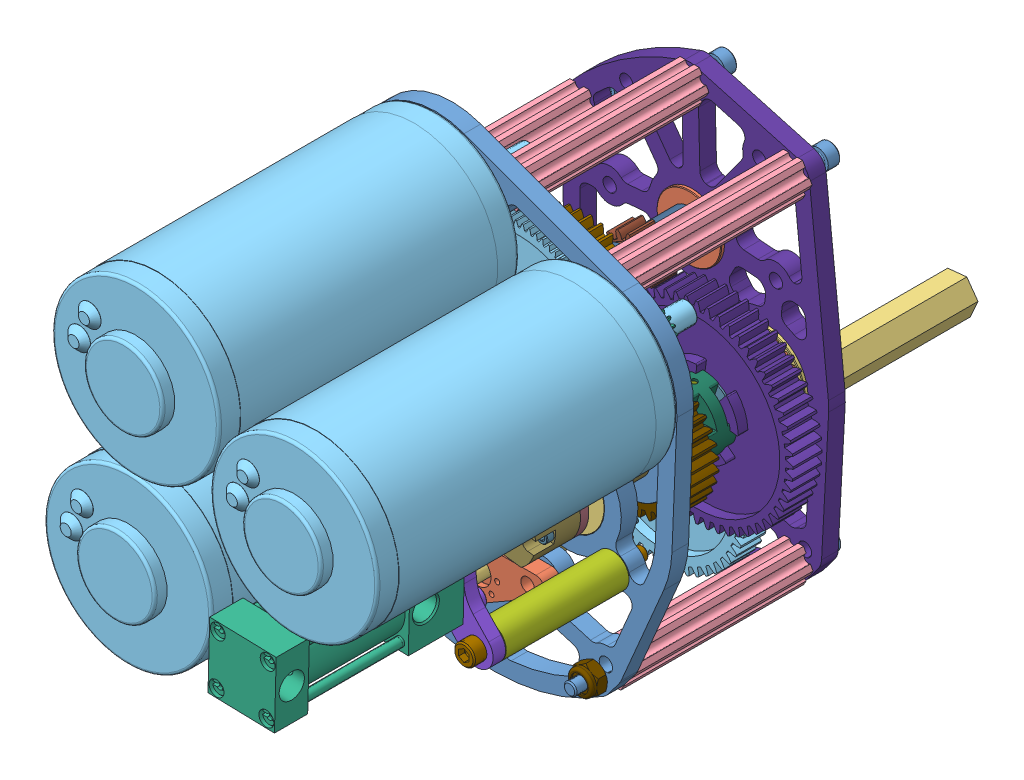
SolidWorks assembly 3+Stage+3+Motor+Evo+Shifter, configuration Default. Lengths in mm.
Overall size (147.1 191.5 302.02).
70 component instances, 41 part files, 6 mates.
Components (placement in the parent):
- 3 Stage 3 Motor Evo Shifter Motor Plate-1: 3 Stage 3 Motor Evo Shifter Motor Plate [Default] at (-18.6795 -53.4915 5.1066) size (126.96 174.09 6.35)
- FR6ZZ Bearing-1: FR6ZZ Bearing [Default] at (-9.8179 13.4916 3.5826) size (24.69 24.69 7.16)
- FR6ZZ Bearing-2: FR6ZZ Bearing [Default] at (-9.8179 -59.5334 3.5826) size (24.69 24.69 7.16)
- FR8ZZ Bearing-1: FR8ZZ Bearing [Default] at (18.3212 -21.016 3.5318) size (31.75 31.75 7.95)
- 3 Stage Cluster Shaft-1: 3 Stage Cluster Shaft [Default] at (-18.6795 19.5335 -63.0924) x (0.828082 0.560606 0) z (0 0 1) size (11 9.53 79.38)
- 85T 32DP 375 Hex Bore Gear-1: 85T 32DP 375 Hex Bore Gear [Default] at (-18.6795 19.5335 1.9951) x (0 0 -1) z (0.899541 -0.436837 0) size (15.88 69.04 69.05)
- 15T 32DP 8mm Bore Gear-1: 15T 32DP 8mm Bore Gear [Default] at (-40.9045 52.5216 5.1066) x (0 0 -1) z (1 0 0) size (19.05 13.38 13.45)
- 15T 32DP 8mm Bore Gear-2: 15T 32DP 8mm Bore Gear [Default] at (-43.8524 -11.264 5.1066) x (0 0 -1) z (1 0 0) size (19.05 13.38 13.45)
- 15T 32DP 8mm Bore Gear-3: 15T 32DP 8mm Bore Gear [Default] at (19.6041 30.3285 5.1066) x (0 0 -1) z (0.999853 0.017124 0) size (19.05 13.38 13.45)
- 1.867 Spacer-1: 1.867 Spacer [Default] at (26.9439 -41.0364 58.8784) x (1 0 0) z (0 1 0) size (12.7 47.42 12.7)
- 1.867 Spacer-2: 1.867 Spacer [Default] at (-8.0246 -4.1874 58.8784) x (1 0 0) z (0 1 0) size (12.7 47.42 12.7)
- 3 Stage Evo Shifter Cylinder Mount Plate-1: 3 Stage Evo Shifter Cylinder Mount Plate [Default] at (9.4597 -14.974 58.8784) x (0.688355 -0.725374 0) z (0 0 1) size (63.5 25.4 4.76)
- 38T 20DP 375Hex 375 FW-1: 38T 20DP 375Hex 375 FW [Default] at (-18.6795 19.5335 -23.4049) x (0 0 1) z (0.071458 -0.997444 0) size (12.7 50.68 50.8)
- .440 ID .500lg Bronze Sleeve Bearing-1: .440 ID .500lg Bronze Sleeve Bearing [Default] at (-18.6795 19.5335 -37.6924) size (14.29 14.29 12.7)
- .440 ID .500lg Bronze Sleeve Bearing-2: .440 ID .500lg Bronze Sleeve Bearing [Default] at (-18.6795 19.5335 -63.0924) size (14.29 14.29 12.7)
- 14T 20dp 375hex 375 FW_Inch - Spur gear 20DP 14T 14.5PA .568FW ---S14N3.0H2.0L0.25N-1: 14T 20dp 375hex 375 FW_Inch - Spur gear 20DP 14T 14.5PA .568FW ---S14N3.0H2.0L0.25N [Default] at (-18.6795 19.5335 -48.8049) x (0 0 1) z (-0.828082 -0.560606 0) size (12.7 19.97 20.32)
- .625t x .504ID 13RS062062 Spacer-1: .625t x .504ID 13RS062062 Spacer [Default] at (9.4597 -14.974 -12.3432) size (15.75 15.75 15.88)
- 3 Stage Evo Shifter Shifting Shaft-1: 3 Stage Evo Shifter Shifting Shaft [Default] at (9.4597 -14.974 10.7581) x (0.990681 -0.1362 0) z (0 0 -1) size (14.66 12.7 81.52)
- 500-e-klip-1: 500-e-klip [Default] at (9.4597 -14.974 -21.5405) x (0.989873 -0.141955 0) z (0 0 1) size (19.07 20.96 1.27)
- 500-e-klip-2: 500-e-klip [Default] at (9.4597 -14.974 -42.7064) x (0.999209 -0.039758 0) z (0 0 1) size (19.07 20.96 1.27)
- 4 Tooth Dog Assem-1: 4 Tooth Dog Assem [Default] at (16.9914 -0.9175 -22.1819) x (-0.990681 0.1362 0) z (0 0 1) size (25.4 25.4 10.67)
  - 4 Tooth Dog-1: 4 Tooth Dog [Default] at (5.547 14.9514 -15.1168) size (25.4 25.4 10.67)
  - .125 dia x 0.625 lg shoulder screw-1: .125 dia x 0.625 lg shoulder screw [Default] at (5.547 26.0639 -13.0848) x (1 0 0) z (0 1 0) size (6.35 6.35 23.22)
- 56T 20DP Dog Pattern Gear-1: 56T 20DP Dog Pattern Gear [Default] at (9.4597 -14.974 -47.5222) x (0 0 1) z (0.923728 0.383049 0) size (11.12 73.59 73.59)
- 32T 20DP 4 Tooth Dog Pattern Gear-1: 32T 20DP 4 Tooth Dog Pattern Gear [Default] at (9.4597 -14.974 -13.8672) x (0 0 -1) z (-0.923728 -0.383049 0) size (11.11 43.04 43.04)
- FR8ZZ Hex Bearing-1: FR8ZZ Hex Bearing [Default] at (9.4597 -14.974 -42.7064) x (0.990681 -0.1362 0) z (0 0 -1) size (31.12 31.12 7.93)
- FR8ZZ Hex Bearing-2: FR8ZZ Hex Bearing [Default] at (9.4597 -14.974 -20.2705) x (-0.990681 0.1362 0) z (0 0 1) size (31.12 31.12 7.93)
- 25T 20DP 500hex 375 FW-1: 25T 20DP 500hex 375 FW [Default] at (9.4597 -14.974 -61.7462) x (0 0 1) z (0.377388 -0.926055 0) size (12.7 34.21 34.27)
- 3 Stage Evo Shifter AM14U3 Hex Output Shaft-1: 3 Stage Evo Shifter AM14U3 Hex Output Shaft [Default] at (-18.6795 -53.4915 9.9326) x (0.411366 0.91147 0) z (0 0 -1) size (14.66 12.7 176.23)
- 500-e-klip-3: 500-e-klip [Default] at (-18.6795 -53.4915 -36.1684) x (0.989873 -0.141955 0) z (0 0 1) size (19.07 20.96 1.27)
- .560t x .600 ID 13RS069038 Spacer-1: .560t x .600 ID 13RS069038 Spacer [Default] at (-18.6795 -53.4915 -50.3924) size (17.27 17.27 14.22)
- 50T 20DP 500hex 375 FW-1: 50T 20DP 500hex 375 FW [Default] at (-18.6795 -53.4915 -51.9799) x (0 0 -1) z (0.411366 0.91147 0) size (12.7 65.97 66.04)
- FR8ZZ Bearing-2: FR8ZZ Bearing [Default] at (3.5884 -23.9496 -63.3337) x (-0.923728 -0.383049 0) z (0 0 -1) size (31.75 31.75 7.95)
- FR8ZZ Hex Bearing-3: FR8ZZ Hex Bearing [Default] at (-18.6795 -53.4915 -71.0197) x (-0.995039 -0.099482 0) z (0 0 1) size (31.12 31.12 7.93)
- FR6ZZ Bearing-3: FR6ZZ Bearing [Default] at (-24.5508 10.558 -63.0924) x (-0.923728 -0.383049 0) z (0 0 -1) size (24.69 24.69 7.16)
- GEN3 Shift Cylinder Body-1: GEN3 Shift Cylinder Body [Default] at (9.4597 -14.974 73.3183) x (0.026177 0.999657 0) z (0.999657 -0.026177 0) size (25.4 75.26 25.4)
- 10-32x0625_shcs_HX-SHCS 0.19-32x1.375x1-C-1: 10-32x0625_shcs_HX-SHCS 0.19-32x1.375x1-C [Default] at (-25.7352 -29.0664 0.2806) x (0 0 1) z (-1 0 0) size (20.7 7.94 7.94)
- 10-32x0625_shcs_HX-SHCS 0.19-32x1.375x1-C-2: 10-32x0625_shcs_HX-SHCS 0.19-32x1.375x1-C [Default] at (19.6041 4.9285 0.2806) x (0 0 1) z (-1 0 0) size (20.7 7.94 7.94)
- 10-32x0625_shcs_HX-SHCS 0.19-32x1.375x1-C-3: 10-32x0625_shcs_HX-SHCS 0.19-32x1.375x1-C [Default] at (-61.9696 6.5384 0.2806) x (0 0 1) z (-1 0 0) size (20.7 7.94 7.94)
- 8-32 x 0500 SHCS-1: 8-32 x 0500 SHCS [Default] at (18.7321 -24.7451 58.8784) x (0 0 1) z (-1 0 0) size (17.34 6.86 6.86)
- 8-32 x 0500 SHCS-2: 8-32 x 0500 SHCS [Default] at (0.1873 -5.203 58.8784) x (0 0 1) z (-1 0 0) size (17.34 6.86 6.86)
- 10-32x2500_shcs_HX-SHCS 0.19-32x1.375x1-C-1: 10-32x2500_shcs_HX-SHCS 0.19-32x1.375x1-C [Default] at (26.9439 -33.3985 68.4669) x (0 0 -1) z (1 0 0) size (68.33 7.94 7.94)
- 10-32x2500_shcs_HX-SHCS 0.19-32x1.375x1-C-2: 10-32x2500_shcs_HX-SHCS 0.19-32x1.375x1-C [Default] at (-8.0246 3.4505 68.4669) x (0 0 -1) z (1 0 0) size (68.33 7.94 7.94)
- am-3451 GEN3 Shifter Shift Assembly-1: am-3451 GEN3 Shifter Shift Assembly [Default] at (-5.8469 23.7522 67.0861) x (0 0 1) z (0.990681 -0.1362 0) size (76.33 18.92 25.4)
  - Shift Shaft-1: Shift Shaft [Default] at (-107.128 36.2806 20.4385) size (64.07 8.26 8.26)
  - 60355K503_BALL BEARING_60355K503-1: 60355K503_BALL BEARING_60355K503 [Default] at (-45.4377 36.2806 20.4385) x (0 0.012082 -0.999927) z (1 0 0) size (15.88 15.88 4.76)
  - Shift Block-1: Shift Block [Default] at (-30.801 36.2806 20.4385) x (0 0 1) z (0 -1 0) size (25.4 17.14 18.92)
  - Shift Block Cap-1: Shift Block Cap [Default] at (-47.946 36.2806 20.4385) x (0 0 1) z (-1 0 0) size (25.4 18.92 3.17)
  - 4-40 x .500 SHCS with threads_90128A110-1: 4-40 x .500 SHCS with threads_90128A110 [Default] at (-51.121 36.2806 30.5985) x (0 0 1) z (-1 0 0) size (4.65 4.65 15.68)
  - 4-40 x .500 SHCS with threads_90128A110-2: 4-40 x .500 SHCS with threads_90128A110 [Default] at (-51.121 36.2806 10.2785) x (0 0 1) z (-1 0 0) size (4.65 4.65 15.68)
  - BHCS 10-32 x 0.25_SBHCSCREW 0.19-32x0.25-HX-C-1: BHCS 10-32 x 0.25_SBHCSCREW 0.19-32x0.25-HX-C [Default] at (-40.4911 36.2806 20.4385) x (-1 0 0) z (0 -0.924225 -0.381849) size (9.43 9.29 9.24)
- GEN3 Shift Cylinder Rod Asm-1: GEN3 Shift Cylinder Rod Asm [Default] at (59.4975 36.6056 56.5364) x (0.990539 0.137232 0) z (0.137232 -0.990539 0) size (19.18 70.31 19.18)
- 3 Stage 3 Motor Evo Shifter Output Plate-1: 3 Stage 3 Motor Evo Shifter Output Plate [Default] at (-18.6794 -53.4913 -70.9664) x (1 -0.000005 0) z (0 0 1) size (101.58 162.88 6.35)
- 10-32 Nylock Nut-1: 10-32 Nylock Nut [Default] at (19.9666 -71.8023 11.4566) size (9.53 11 5.96)
- 10-32 Nylock Nut-2: 10-32 Nylock Nut [Default] at (-57.3256 -71.8023 11.4566) size (9.53 11 5.96)
- SHCS 10-32 x 3.75_HX-SHCS 0.19-32x3.5x1.125-C-1: SHCS 10-32 x 3.75_HX-SHCS 0.19-32x3.5x1.125-C [Default] at (19.9666 -71.8023 -78.9674) x (0 0 1) z (-1 0 0) size (100.08 7.94 7.94)
- SHCS 10-32 x 3.75_HX-SHCS 0.19-32x3.5x1.125-C-2: SHCS 10-32 x 3.75_HX-SHCS 0.19-32x3.5x1.125-C [Default] at (19.6041 55.7285 -78.9674) x (0 0 1) z (-1 0 0) size (100.08 7.94 7.94)
- SHCS 10-32 x 3.75_HX-SHCS 0.19-32x3.5x1.125-C-3: SHCS 10-32 x 3.75_HX-SHCS 0.19-32x3.5x1.125-C [Default] at (-19.8393 66.7138 -78.9674) x (0 0 1) z (0.972468 0.233037 0) size (100.08 7.94 7.94)
- SHCS 10-32 x 3.75_HX-SHCS 0.19-32x3.5x1.125-C-4: SHCS 10-32 x 3.75_HX-SHCS 0.19-32x3.5x1.125-C [Default] at (-57.3256 -71.8023 -78.9674) x (0 0 1) z (-1 0 0) size (100.08 7.94 7.94)
- SHCS 10-32 x 3.75_HX-SHCS 0.19-32x3.5x1.125-C-5: SHCS 10-32 x 3.75_HX-SHCS 0.19-32x3.5x1.125-C [Default] at (-61.9696 38.3294 -78.9674) x (0 0 1) z (0.972468 0.233037 0) size (100.08 7.94 7.94)
- am-0208 Encoder Mount Pad-1: am-0208 Encoder Mount Pad [Default] at (-18.6795 -53.4915 11.4566) x (0 -1 0) z (-1 0 0) size (19.05 6.1 50.8)
- 250x1000 dowel-1: 250x1000 dowel [Default] at (-18.6795 -53.4915 -1.2434) x (1 0 0) z (0 -1 0) size (6.35 25.41 6.35)
- 3 Stage Evo Shifter Plate Spacer Churro Version-1: 3 Stage Evo Shifter Plate Spacer Churro Version [Default] at (19.6041 55.7285 -64.6164) size (14.66 12.7 69.85)
- 3 Stage Evo Shifter Plate Spacer Churro Version-2: 3 Stage Evo Shifter Plate Spacer Churro Version [Default] at (19.9666 -71.8023 -64.6164) size (14.66 12.7 69.85)
- 3 Stage Evo Shifter Plate Spacer Churro Version-3: 3 Stage Evo Shifter Plate Spacer Churro Version [Default] at (-57.3256 -71.8023 -64.6164) size (14.66 12.7 69.85)
- 3 Stage Evo Shifter Plate Spacer Churro Version-4: 3 Stage Evo Shifter Plate Spacer Churro Version [Default] at (-61.9696 38.3294 -64.6164) size (14.66 12.7 69.85)
- 3 Stage Evo Shifter Plate Spacer Churro Version-5: 3 Stage Evo Shifter Plate Spacer Churro Version [Default] at (-19.8393 66.7138 -64.6164) size (14.66 12.7 69.85)
- am-0255+2.5inch+CIM+Motor-1: am-0255+2.5inch+CIM+Motor [Default] at (33.8091 -34.8172 30.5066) x (-0.923728 -0.383049 0) z (0 0 -1) size (64.01 64.01 154.94)
- am-0255+2.5inch+CIM+Motor-2: am-0255+2.5inch+CIM+Motor [Default] at (94.3176 -57.0102 30.5066) x (-0.923728 -0.383049 0) z (0 0 -1) size (64.01 64.01 154.94)
- am-0255+2.5inch+CIM+Motor-3: am-0255+2.5inch+CIM+Motor [Default] at (30.8612 -98.6027 30.5066) x (-0.923728 -0.383049 0) z (0 0 -1) size (64.01 64.01 154.94)
Mates (geometry in assembly coordinates):
- Coincident1: coincident anti-aligned: plane of 3 Stage 3 Motor Evo Shifter Motor Plate-1 through (-18.6795 -13.6173 11.4566) normal (0 0 1); plane of am-0255+2.5inch+CIM+Motor-1 through (-40.9045 52.5216 11.4566) normal (0 0 -1)
- Concentric1: concentric anti-aligned: cylinder of 3 Stage 3 Motor Evo Shifter Motor Plate-1 through (-40.9045 52.5216 11.4566) axis (0 0 -1) radius 9.525; cylinder of am-0255+2.5inch+CIM+Motor-1 through (-40.9045 52.5216 7.3926) axis (0 0 1) radius 9.525
- Coincident2: coincident anti-aligned: plane of 3 Stage 3 Motor Evo Shifter Motor Plate-1 through (-18.6795 -13.6173 11.4566) normal (0 0 1); plane of am-0255+2.5inch+CIM+Motor-2 through (19.6041 30.3285 11.4566) normal (0 0 -1)
- Concentric2: concentric anti-aligned: cylinder of 3 Stage 3 Motor Evo Shifter Motor Plate-1 through (19.6041 30.3285 11.4566) axis (0 0 -1) radius 9.525; cylinder of am-0255+2.5inch+CIM+Motor-2 through (19.6041 30.3285 7.3926) axis (0 0 1) radius 9.525
- Coincident4: coincident: plane of 3 Stage 3 Motor Evo Shifter Motor Plate-1 through (-18.6795 -13.6173 11.4566) normal (0 0 1); plane of am-0255+2.5inch+CIM+Motor-3 through (-43.8524 -11.264 11.4566) normal (0 0 -1)
- Concentric3: concentric anti-aligned: cylinder of 3 Stage 3 Motor Evo Shifter Motor Plate-1 through (-43.8524 -11.264 11.4566) axis (0 0 -1) radius 9.525; cylinder of am-0255+2.5inch+CIM+Motor-3 through (-43.8524 -11.264 7.3926) axis (0 0 1) radius 9.525
